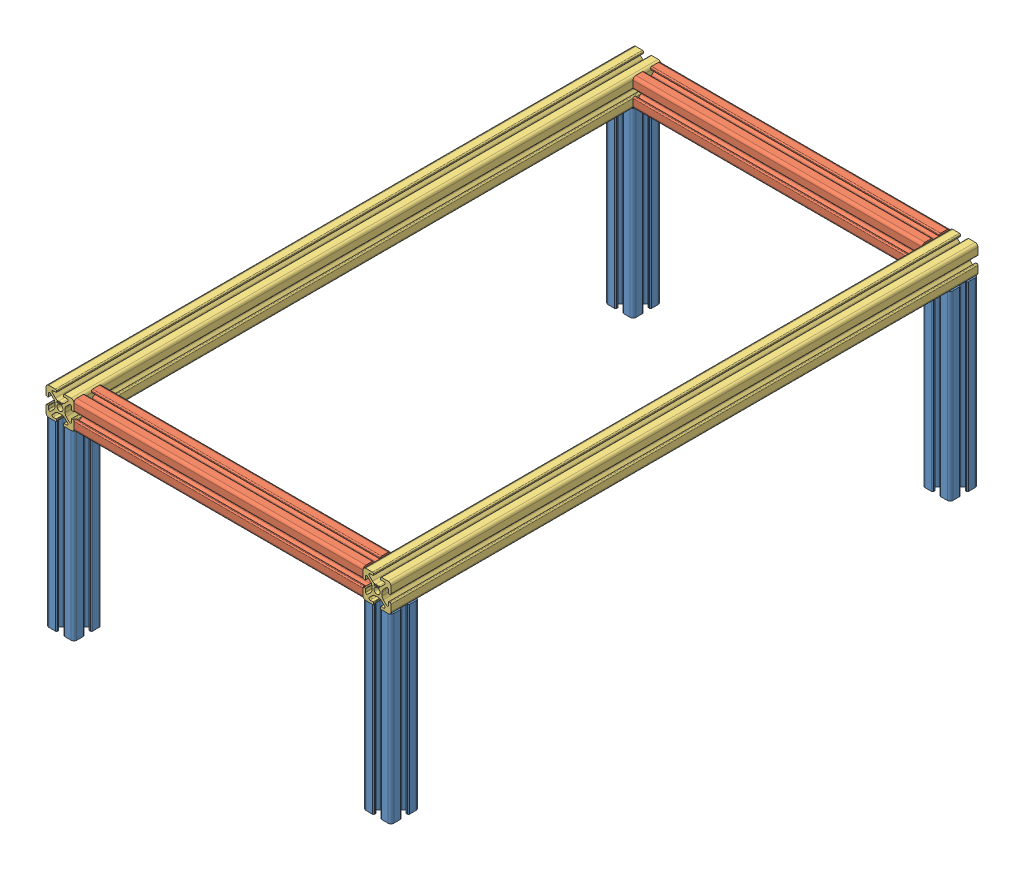
SolidWorks assembly Mounting Frame, configuration Default. Lengths in mm.
Overall size (246.8 150.09 420.1).
10 component instances, 4 part files, 26 mates.
Components (placement in the parent):
- Vertical Beam-1: Vertical Beam [Default] at (-12.7433 375.5327 464.8294) x (0 0 -1) z (0 -1 0) size (19.99 19.99 130.1)
- Vertical Beam-2: Vertical Beam [Default] at (-12.7433 375.5327 64.8192) x (1 0 0) z (0 -1 0) size (19.99 19.99 130.1)
- Vertical Beam-3: Vertical Beam [Default] at (214.0665 375.5327 64.8192) x (1 0 0) z (0 -1 0) size (19.99 19.99 130.1)
- Vertical Beam-4: Vertical Beam [Default] at (214.0665 375.5327 464.8294) x (0 0 1) z (0 -1 0) size (19.99 19.99 130.1)
- Top  parallel horontal Beam 250mm-1: Top  parallel horontal Beam 250mm [Default] at (-2.7484 385.5276 464.8294) x (0 -1 0) z (1 0 0) size (19.99 19.99 206.92)
- Top  parallel horontal Beam 250mm-2: Top  parallel horontal Beam 250mm [Default] at (204.0716 385.5276 64.8192) x (0 0 1) z (-1 0 0) size (19.99 19.99 206.92)
- Top horontal Beam-1: Top horontal Beam [Default] at (214.0665 385.5276 54.8243) size (19.99 19.99 420.1)
- Top horontal Beam-2: Top horontal Beam [Default] at (-12.7433 385.5276 54.8243) size (19.99 19.99 420.1)
- 5537T935_ALUMINUM T-SLOTTED FRAMING EXTRUSION (20mm)-1: 5537T935_ALUMINUM T-SLOTTED FRAMING EXTRUSION (20mm) [5537T935] at (204.0716 385.5276 74.8141) x (-1 0 0) z (0 1 0) (suppressed, hidden)
- 5537T935_ALUMINUM T-SLOTTED FRAMING EXTRUSION (20mm)-2: 5537T935_ALUMINUM T-SLOTTED FRAMING EXTRUSION (20mm) [5537T935] at (204.0716 375.5327 64.8192) x (0 -1 0) z (0 0 -1) (suppressed, hidden)
Mates (geometry in assembly coordinates):
- Parallel4: parallel aligned: plane of Vertical Beam-4 through (224.0614 245.5327 472.8177) normal (1 0 0); plane of Top horontal Beam-1 through (224.0614 377.5393 474.8243) normal (1 0 0)
- Parallel5: parallel aligned: plane of Vertical Beam-4 through (222.0548 245.5327 474.8243) normal (0 0 1); plane of Top horontal Beam-1 through (212.9331 392.1527 474.8243) normal (0 0 1)
- Coincident19: coincident: point of Vertical Beam-4; point of Top horontal Beam-1
- Coincident20: coincident anti-aligned: plane of Top  parallel horontal Beam 250mm-1 through (204.0716 386.661 458.2043) normal (1 0 0); plane of Top horontal Beam-1 through (204.0716 393.5159 474.8243) normal (-1 0 0)
- Coincident21: coincident: point of Top  parallel horontal Beam 250mm-1; point of Top horontal Beam-1
- Parallel6: parallel aligned: plane of Top  parallel horontal Beam 250mm-1 through (204.0716 395.5225 472.8177) normal (0 1 0); plane of Top horontal Beam-1 through (206.0782 395.5225 474.8243) normal (0 1 0)
- Coincident26: coincident anti-aligned: plane of Top  parallel horontal Beam 250mm-2 through (204.0716 392.1527 63.6858) normal (1 0 0); plane of Top horontal Beam-1 through (204.0716 393.5159 474.8243) normal (-1 0 0)
- Coincident27: coincident aligned: plane of Top  parallel horontal Beam 250mm-2 through (-2.7484 393.5159 54.8243) normal (0 0 -1); plane of Top horontal Beam-1 through (212.9331 392.1527 54.8243) normal (0 0 -1)
- Coincident28: coincident: point of Top  parallel horontal Beam 250mm-2; point of Top horontal Beam-1
- Parallel9: parallel aligned: plane of Vertical Beam-2 through (-20.7316 245.5327 54.8243) normal (0 0 -1); plane of Top horontal Beam-2 through (-13.8767 392.1527 54.8243) normal (0 0 -1)
- Coincident30: coincident aligned: plane of Vertical Beam-2 through (-22.7382 245.5327 56.8309) normal (-1 0 0); plane of Top horontal Beam-2 through (-22.7382 393.5159 474.8243) normal (-1 0 0)
- Coincident31: coincident: point of Vertical Beam-2; point of Top horontal Beam-2
- Coincident32: coincident anti-aligned: plane of Top  parallel horontal Beam 250mm-2 through (-2.7484 392.1527 63.6858) normal (-1 0 0); plane of Top horontal Beam-2 through (-2.7484 393.5159 474.8243) normal (1 0 0)
- Coincident33: coincident aligned: plane of Top  parallel horontal Beam 250mm-2 through (-2.7484 393.5159 54.8243) normal (0 0 -1); plane of Top horontal Beam-2 through (-13.8767 392.1527 54.8243) normal (0 0 -1)
- Coincident34: coincident: point of Top  parallel horontal Beam 250mm-2; point of Top horontal Beam-2
- Parallel10: parallel anti-aligned: plane of Top horontal Beam-1 through (204.0716 393.5159 474.8243) normal (-1 0 0); plane of 5537T935_ALUMINUM T-SLOTTED FRAMING EXTRUSION (20mm)-1 through (204.0716 394.5276 74.8141) normal (1 0 0)
- Coincident37: coincident anti-aligned: plane of Top  parallel horontal Beam 250mm-2 through (-2.7484 393.5159 74.8141) normal (0 0 1); plane of 5537T935_ALUMINUM T-SLOTTED FRAMING EXTRUSION (20mm)-1 through (184.0716 394.5276 74.8141) normal (0 0 -1)
- Coincident38: coincident anti-aligned: line of Top  parallel horontal Beam 250mm-2 through (204.0716 388.8169 74.8141) axis (0 1 0); line of 5537T935_ALUMINUM T-SLOTTED FRAMING EXTRUSION (20mm)-1 through (204.0716 394.5276 74.8141) axis (0 -1 0)
- Width1: width anti-aligned: plane of 5537T935_ALUMINUM T-SLOTTED FRAMING EXTRUSION (20mm)-1 through (204.0716 394.5276 91.8141) normal (0 1 0); plane of 5537T935_ALUMINUM T-SLOTTED FRAMING EXTRUSION (20mm)-1 through (204.0716 376.5276 91.8141) normal (0 -1 0); plane of Top horontal Beam-1 through (206.0782 375.5327 474.8243) normal (0 -1 0); plane of Top horontal Beam-1 through (206.0782 395.5225 474.8243) normal (0 1 0)
- Width2: width anti-aligned: plane of 5537T935_ALUMINUM T-SLOTTED FRAMING EXTRUSION (20mm)-2 through (187.0716 375.5327 55.8192) normal (0 0 -1); plane of 5537T935_ALUMINUM T-SLOTTED FRAMING EXTRUSION (20mm)-2 through (187.0716 375.5327 73.8192) normal (0 0 1); plane of Vertical Beam-3 through (206.0782 245.5327 74.8141) normal (0 0 1); plane of Vertical Beam-3 through (206.0782 245.5327 54.8243) normal (0 0 -1)
- Coincident39: coincident anti-aligned: line of Vertical Beam-3 through (204.0716 375.5327 61.5299) axis (0 0 -1); line of 5537T935_ALUMINUM T-SLOTTED FRAMING EXTRUSION (20mm)-2 through (204.0716 375.5327 55.8192) axis (0 0 1)
- Coincident40: coincident anti-aligned: plane of Top  parallel horontal Beam 250mm-2 through (-2.7484 375.5327 56.8309) normal (0 -1 0); plane of 5537T935_ALUMINUM T-SLOTTED FRAMING EXTRUSION (20mm)-2 through (204.0716 375.5327 55.8192) normal (0 1 0)
- Coincident41: coincident aligned: plane of Vertical Beam-1 through (-20.7316 245.5327 474.8243) normal (0 0 1); plane of Top horontal Beam-2 through (-13.8767 392.1527 474.8243) normal (0 0 1)
- Coincident42: coincident: moEndPointRef_w of Vertical Beam-1; plane of Top horontal Beam-2 through (-20.7316 375.5327 474.8243) normal (0 -1 0)
- Coincident43: coincident aligned: plane of Vertical Beam-1 through (-22.7382 245.5327 472.8177) normal (-1 0 0); plane of Top horontal Beam-2 through (-22.7382 377.5393 474.8243) normal (-1 0 0)
- Coincident44: coincident aligned: plane of Vertical Beam-3 through (206.0782 245.5327 54.8243) normal (0 0 -1); plane of Top horontal Beam-1 through (212.9331 392.1527 54.8243) normal (0 0 -1)
